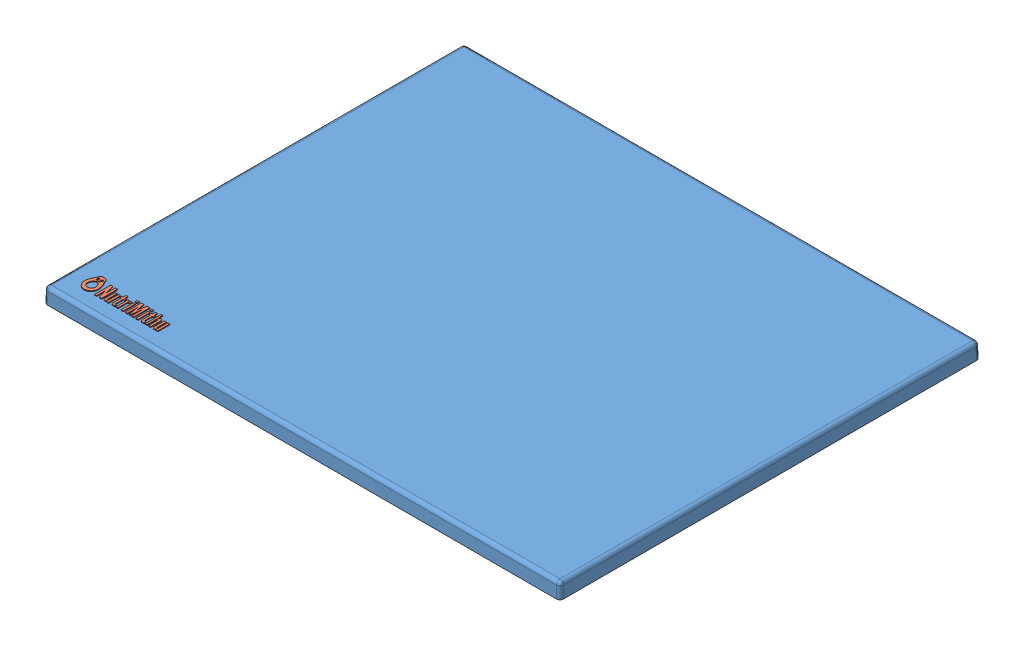
SolidWorks assembly nutrimithu_assem1, configuration Default. Lengths in mm.
Overall size (215.17 6.8 175.17).
2 component instances, 2 part files, 1 mates.
Components (placement in the parent):
- lid-2: lid [Default] at (55.3118 116.0504 185.6593) size (215.17 6.5 175.17)
- logo2-1: logo2 [Default] at (-51.7919 117.5504 284.5711) size (33.41 0.3 8.33)
Mates (geometry in assembly coordinates):
- Lock4: lock: unknown of lid-2; unknown of logo2-1
